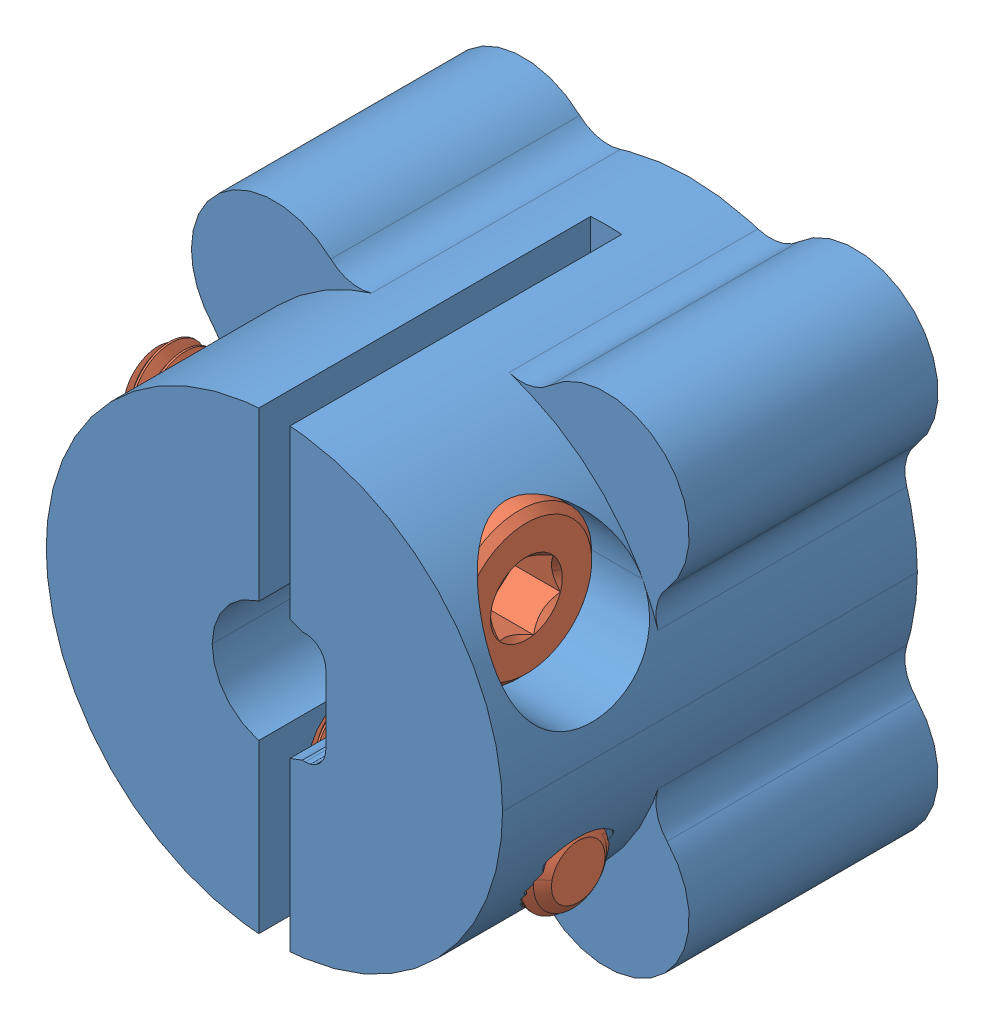
SolidWorks assembly 6mm D-bore Hyper Hub 1310-0016-1006, configuration Default. Lengths in mm.
Overall size (24 24 22).
3 component instances, 2 part files, 0 mates.
Components (placement in the parent):
- 1310-0016-1006.STEP-1: 1310-0016-1006.STEP [Default] at (-34.7825 -1.5018 9.8745) size (24 24 22)
- 2800-0004-0014_90128A207.STEP-1: 2800-0004-0014_90128A207.STEP [Default] at (-45.0325 3.5767 25.4745) x (0 -0.199578 0.979882) z (-1 0 0) size (7 7 18.01)
- 2800-0004-0014_90128A207.STEP-2: 2800-0004-0014_90128A207.STEP [Default] at (-24.5325 -6.5802 25.4745) x (0 0.199578 0.979882) z (1 0 0) size (7 7 18.01)
